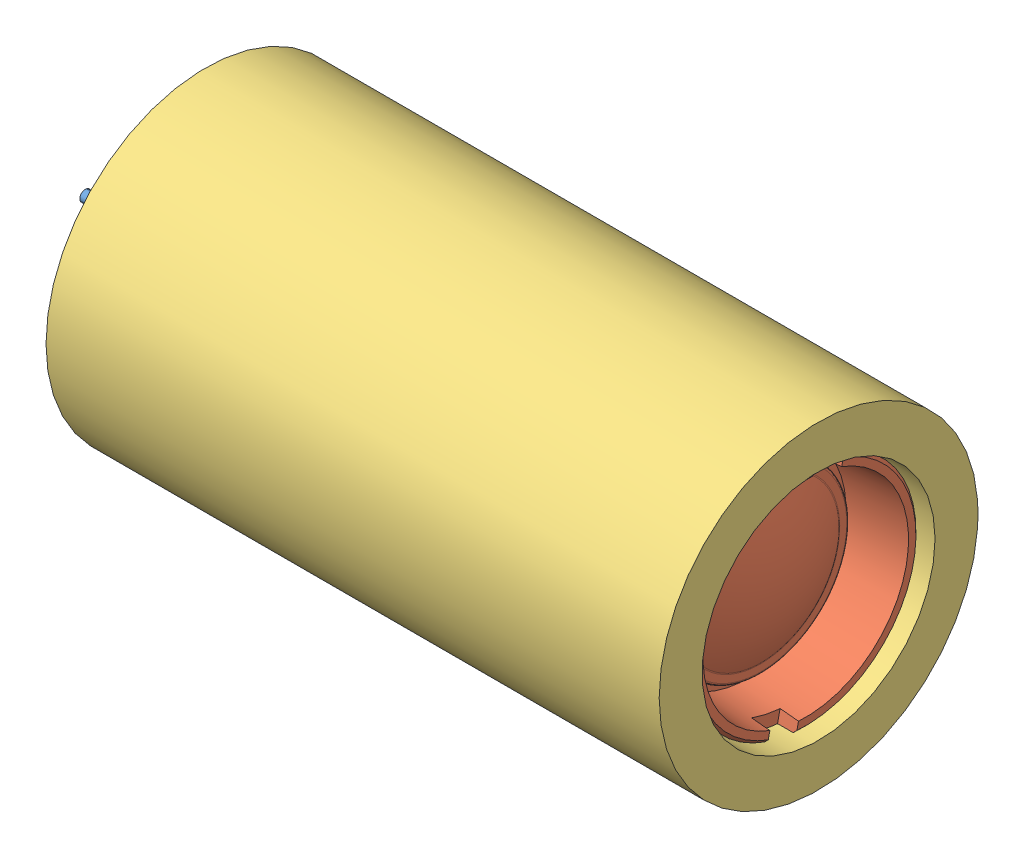
SolidWorks assembly colimation tube assembly final, configuration Default. Lengths in mm.
Overall size (29 13 13).
3 component instances, 3 part files, 3 mates.
Components (placement in the parent):
- diode-1: diode [Default] at (-37.8768 1.4091 16.9409) x (0 0 1) z (-1 0 0) size (9 9 14.45)
- C220TME-B-Solidworks-1: C220TME-B-Solidworks [Default] at (-29.1282 1.4091 16.9409) x (0 -0.977212 0.212268) z (0 0.212268 0.977212) size (9.24 7.19 9.24)
- colimation tube final ver2-1: colimation tube final ver2 [Default] at (-46.4182 1.4091 22.5957) x (0 0 -1) z (1 0 0) size (13 13 25)
Mates (geometry in assembly coordinates):
- Distance1: distance = 6.84 mm anti-aligned: plane of C220TME-B-Solidworks-1 through (-29.1282 -1.7556 17.6283) normal (-1 0 0); plane of diode-1 through (-35.9682 1.4091 16.9409) normal (1 0 0)
- Coincident1: coincident anti-aligned: plane of diode-1 through (-38.9182 1.4091 16.9409) normal (1 0 0); plane of colimation tube final ver2-1 through (-38.9182 1.4091 16.9409) normal (-1 0 0)
- Concentric1: concentric anti-aligned: circle of diode-1; circle of colimation tube final ver2-1
